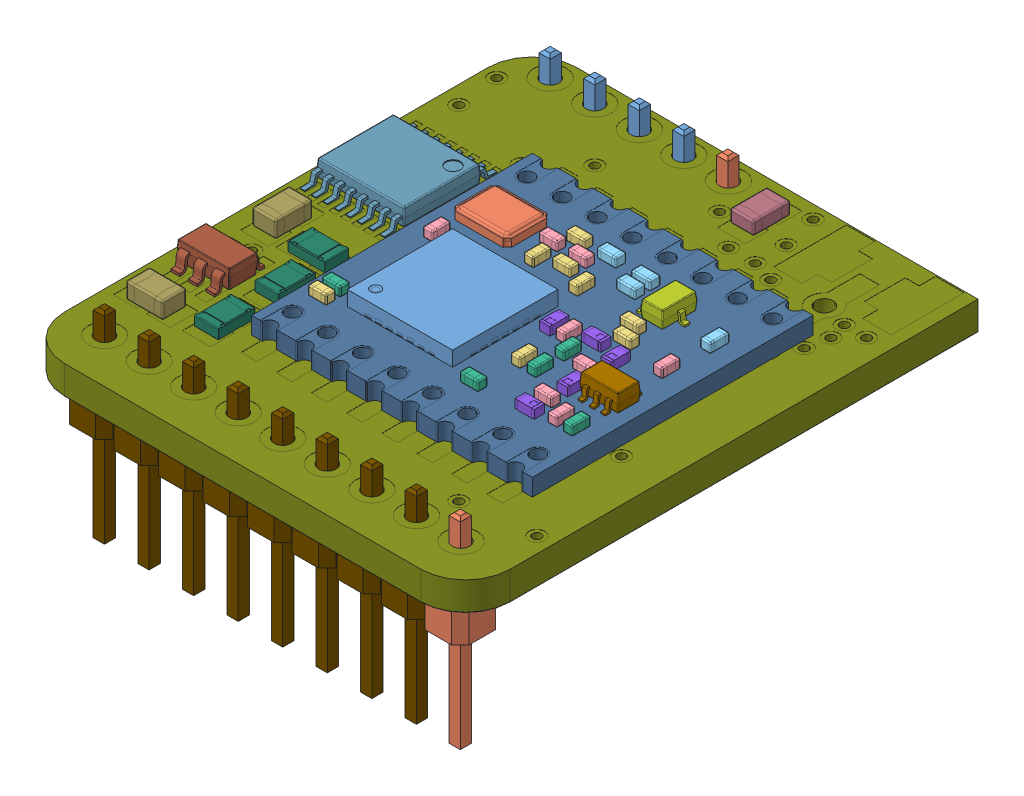
SolidWorks assembly RFM95W v5, configuration Default. Lengths in mm.
Overall size (25.4 12.17 29.21).
51 component instances, 20 part files, 12 mates.
Components (placement in the parent):
- RFM95W v5.step-1: RFM95W v5.step [Default] at origin size (25.4 3.63 29.21)
  - RFM95.step-1: RFM95.step [Default] at (22.732 1.58 -22.732) x (0 0 1) z (-1 0 0) size (16 2.04 16)
    - QFN 28 v2.step-1: QFN 28 v2.step [Default] at (9.4 1.05 10.3192) x (0 0 1) z (0 1 0) size (6 6 0.91)
    - SMD Crystal v1.step-1: SMD Crystal v1.step [Default] at (2.99 0.99 15.15) x (0 0 -1) z (1 0 0) size (3.2 0.6 2.5)
    - CAP 0403 v1.step-1: CAP 0403 v1.step [Default] at (5.3 1.275 7.605) size (1.05 0.55 0.55)
    - CAP 0403 v1.step-2: CAP 0403 v1.step [Default] at (5.15 1.275 10.275) size (1.05 0.55 0.55)
    - CAP 0403 v1.step-3: CAP 0403 v1.step [Default] at (10.5 1.275 5.675) size (1.05 0.55 0.55)
    - CAP 0403 v1.step-4: CAP 0403 v1.step [Default] at (2.825 1.275 10.2) x (0 0 -1) z (1 0 0) size (1.05 0.55 0.55)
    - CAP 0403 v1.step-5: CAP 0403 v1.step [Default] at (4.575 1.275 9.25) x (0 0 -1) z (1 0 0) size (1.05 0.55 0.55)
    - CAP 0403 v1.step-6: CAP 0403 v1.step [Default] at (12.875 1.275 14.85) x (0 0 -1) z (1 0 0) size (1.05 0.55 0.55)
    - CAP 0403 v1.step-7: CAP 0403 v1.step [Default] at (5.525 1.275 4.45) x (0 0 -1) z (1 0 0) size (1.05 0.55 0.55)
    - CAP 0403 v1.step-8: CAP 0403 v1.step [Default] at (6.425 1.275 3.95) x (0 0 -1) z (1 0 0) size (1.05 0.55 0.55)
    - CAP Ceramic 0403 v1.step-1: CAP Ceramic 0403 v1.step [Default] at (6.95 1.275 1.125) size (1.05 0.55 0.55)
    - CAP Ceramic 0403 v1.step-2: CAP Ceramic 0403 v1.step [Default] at (12.35 1.275 1.725) size (1.05 0.55 0.55)
    - CAP Ceramic 0403 v1.step-3: CAP Ceramic 0403 v1.step [Default] at (8 1.275 5.625) size (1.05 0.55 0.55)
    - CAP Ceramic 0403 v1.step-4: CAP Ceramic 0403 v1.step [Default] at (6.75 1.275 14.425) size (1.05 0.55 0.55)
    - CAP Ceramic 0403 v1.step-5: CAP Ceramic 0403 v1.step [Default] at (12.075 1.275 3.35) x (0 0 1) z (-1 0 0) size (1.05 0.55 0.55)
    - CAP Ceramic 0403 v1.step-6: CAP Ceramic 0403 v1.step [Default] at (9.525 1.275 3.7) x (0 0 1) z (-1 0 0) size (1.05 0.55 0.55)
    - CAP Ceramic 0403 v1.step-7: CAP Ceramic 0403 v1.step [Default] at (4.225 1.275 9.25) x (0 0 1) z (-1 0 0) size (1.05 0.55 0.55)
    - CAP Ceramic 0403 v1.step-8: CAP Ceramic 0403 v1.step [Default] at (4.225 1.275 10.9) x (0 0 1) z (-1 0 0) size (1.05 0.55 0.55)
    - Res 0403 v1.step-1: Res 0403 v1.step [Default] at (4.3 1.265 1) size (1.1 0.55 0.6)
    - Res 0403 v1.step-2: Res 0403 v1.step [Default] at (4.35 1.265 6.35) x (0 0 1) z (-1 0 0) size (1.1 0.55 0.6)
    - Res 0403 v1.step-3: Res 0403 v1.step [Default] at (3.49 1.265 6.35) x (0 0 1) z (-1 0 0) size (1.1 0.55 0.6)
    - Res 0403 v1.step-4: Res 0403 v1.step [Default] at (3.34 1.265 8.45) x (0 0 1) z (-1 0 0) size (1.1 0.55 0.6)
    - CAP ML 0403 v1.step-1: CAP ML 0403 v1.step [Default] at (10.5 1.275 4.775) size (1.05 0.55 0.55)
    - CAP ML 0403 v1.step-2: CAP ML 0403 v1.step [Default] at (12.35 1.275 0.845) size (1.05 0.55 0.55)
    - CAP ML 0403 v1.step-3: CAP ML 0403 v1.step [Default] at (12.825 1.275 6.25) x (0 0 -1) z (1 0 0) size (1.05 0.55 0.55)
    - CAP ML 0403 v1.step-4: CAP ML 0403 v1.step [Default] at (8.9 1.275 4.775) size (1.05 0.55 0.55)
    - CAP ML 0403 v1.step-5: CAP ML 0403 v1.step [Default] at (12.075 1.275 14.85) x (0 0 -1) z (1 0 0) size (1.05 0.55 0.55)
    - SOT-323 v1.step-1: SOT-323 v1.step [Default] at (4.1 0.9905 4.114) size (2 1 2.12)
    - Inductor SMD 0403 v1.step-1: Inductor SMD 0403 v1.step [Default] at (7.3 1 4.2) size (0.6 0.5 1.1)
    - Inductor SMD 0403 v1.step-2: Inductor SMD 0403 v1.step [Default] at (8.549 1 6.449) x (0 0 1) z (-1 0 0) size (0.6 0.5 1.1)
    - Inductor SMD 0403 v1.step-3: Inductor SMD 0403 v1.step [Default] at (8.549 1 2.949) x (0 0 1) z (-1 0 0) size (0.6 0.5 1.1)
    - Inductor SMD 0403 v1.step-4: Inductor SMD 0403 v1.step [Default] at (11.049 1 2.949) x (0 0 1) z (-1 0 0) size (0.6 0.5 1.1)
    - Inductor SMD 0403 v1.step-5: Inductor SMD 0403 v1.step [Default] at (12.5 1 2.8) size (0.6 0.5 1.1)
    - SOT-363 v1.step-1: SOT-363 v1.step [Default] at (9.85 0.991 1.7207) x (0 0 -1) z (1 0 0) size (2.2 1.05 2.12)
    - RFM95-0.step-1: RFM95-0.step [Default] at origin size (16 1 16)
  - SOT23-5.step-1: SOT23-5.step [Default] at (2.54 1.5797 -8.9813) x (0 0 1) z (0 1 0) size (2.84 3.01 1.19)
  - CAP 0805 T095.step-1: CAP 0805 T095.step [Default] at (2.4321 1.59 -5.588) x (1 0 0) z (0 1 0) size (2.1 1.35 0.95)
  - CAP 0805 T095.step-2: CAP 0805 T095.step [Default] at (2.0321 1.59 -13.188) x (0 0 -1) z (0 1 0) size (2.1 1.35 0.95)
  - CAP 0805 T075.step-1: CAP 0805 T075.step [Default] at (15.494 1.59 -26.9549) x (0 0 -1) z (0 1 0) size (2.1 1.35 0.75)
  - TSSOP16.step-1: TSSOP16.step [Default] at (3.302 1.49 -18.542) x (-1 0 0) z (0 0 -1) size (5 1.1 6.42)
  - RES 0805.step-1: RES 0805.step [Default] at (5.334 1.56 -6.604) x (0 0 -1) z (0 1 0) size (2.1 1.35 0.6)
  - RES 0805.step-2: RES 0805.step [Default] at (5.334 1.56 -10.033) x (0 0 -1) z (0 1 0) size (2.1 1.35 0.6)
  - RES 0805.step-3: RES 0805.step [Default] at (4.699 1.56 -12.573) x (1 0 0) z (0 1 0) size (2.1 1.35 0.6)
  - RFM95W.step-1: RFM95W.step [Default] at origin size (25.4 1.6 29.21)
  - RFM95W-1.step-1: RFM95W-1.step [Default] at origin size (25.4 0.01 29.21)
- 8pins.step-1: 8pins.step [Default] at (2.5395 2.99 -2.535) x (1 0 0) z (0 -1 0) size (20.28 2.5 11.54)
- 4pins.step-1: 4pins.step [Default] at (2.542 2.99 -27.94) x (1 0 0) z (0 -1 0) size (10.12 2.5 11.54)
- 1pins.step-1: 1pins.step [Default] at (22.8195 2.99 -2.535) x (1 0 0) z (0 -1 0) size (2.5 2.5 11.54)
- 1pins.step-2: 1pins.step [Default] at (12.662 2.99 -27.94) x (1 0 0) z (0 -1 0) size (2.5 2.5 11.54)
Mates (geometry in assembly coordinates):
- Coincident1: coincident: plane of RFM95W v5.step-1/RFM95W-1.step-1 through (12.954 -0.01 -14.605) normal (0 -1 0); plane of 8pins.step-1 through (2.5395 -0.01 -2.535) normal (0 1 0)
- Distance1: distance = 1.285 mm: plane of 8pins.step-1 through (1.2895 -0.01 -1.285) normal (0 0 1); plane of RFM95W v5.step-1/RFM95W.step-1 through (2.794 0 0) normal (0 0 1)
- Distance2: distance = 1.0355 mm aligned: plane of 8pins.step-1 through (1.2895 -0.01 -3.785) normal (-1 0 0); plane of RFM95W v5.step-1/RFM95W.step-1 through (0.254 0 -26.67) normal (-1 0 0)
- Coincident4: coincident: plane of RFM95W v5.step-1/RFM95W-1.step-1 through (12.954 -0.01 -14.605) normal (0 -1 0); plane of 1pins.step-1 through (22.8195 -0.01 -2.535) normal (0 1 0)
- Coincident5: coincident: plane of 8pins.step-1 through (21.5695 -0.01 -1.285) normal (1 0 0); plane of 1pins.step-1 through (21.5695 -0.01 -3.785) normal (-1 0 0)
- Coincident6: coincident aligned: plane of 8pins.step-1 through (19.0695 -0.01 -1.285) normal (0 0 1); plane of 1pins.step-1 through (21.5695 -0.01 -1.285) normal (0 0 1)
- Coincident7: coincident anti-aligned: plane of RFM95W v5.step-1/RFM95W-1.step-1 through (12.954 -0.01 -14.605) normal (0 -1 0); plane of 4pins.step-1 through (7.604 -0.01 -27.94) normal (0 1 0)
- Distance3: distance = 1.038 mm aligned: plane of 4pins.step-1 through (1.292 -0.01 -29.19) normal (-1 0 0); plane of RFM95W v5.step-1/RFM95W.step-1 through (0.254 0 -26.67) normal (-1 0 0)
- Distance4: distance = 0.02 mm aligned: plane of 4pins.step-1 through (6.332 -0.01 -29.19) normal (0 0 -1); plane of RFM95W v5.step-1/RFM95W.step-1 through (25.654 0 -29.21) normal (0 0 -1)
- Coincident10: coincident: plane of RFM95W v5.step-1/RFM95W-1.step-1 through (12.954 -0.01 -14.605) normal (0 -1 0); plane of 1pins.step-2 through (12.662 -0.01 -19.7745) normal (0 1 0)
- Coincident11: coincident: plane of 4pins.step-1 through (11.412 -0.01 -26.69) normal (1 0 0); plane of 1pins.step-2 through (11.412 -0.01 -21.0245) normal (-1 0 0)
- Coincident12: coincident aligned: plane of 4pins.step-1 through (11.412 -0.01 -29.19) normal (0 0 -1); plane of 1pins.step-2 through (13.912 -0.01 -29.19) normal (0 0 -1)
